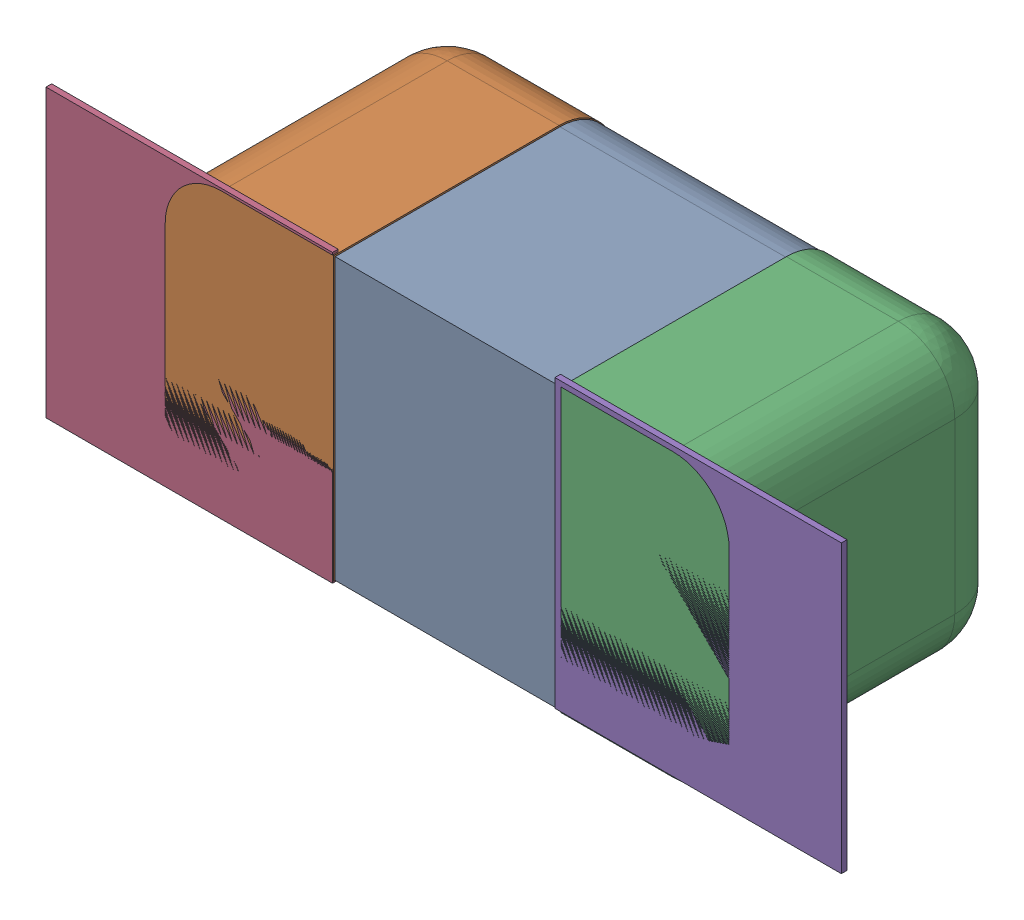
SolidWorks assembly C114, configuration Défaut. Lengths in mm.
Overall size (1.41 0.51 0.5).
8 component instances, 4 part files, 0 mates.
Components (placement in the parent):
- 5458962032-1: 5458962032 [Défaut] at (23.3934 -35.052 -2.0818) x (1 0 0) z (0 1 0) size (1 0.5 0.5)
  - Open CASCADE STEP translator 7.5 2.80.1.1-1: Open CASCADE STEP translator 7.5 2.80.1.1 [Défaut] at origin size (0.4 0.5 0.5)
  - Open CASCADE STEP translator 7.5 2.80.1.2-1: Open CASCADE STEP translator 7.5 2.80.1.2 [Défaut] at origin size (0.3 0.5 0.5)
  - Open CASCADE STEP translator 7.5 2.80.1.3-1: Open CASCADE STEP translator 7.5 2.80.1.3 [Défaut] at origin size (0.3 0.5 0.5)
- 6504207776-1: 6504207776 [Défaut] at (22.9361 -35.052 -2.0918) size (0.51 0.51 0.01)
  - Extruded-1: Extruded [Défaut] at origin size (0.51 0.51 0.01)
- 6504207776-2: 6504207776 [Défaut] at (23.8384 -35.0468 -2.0918) size (0.51 0.51 0.01)
  - Extruded-1: Extruded [Défaut] at origin size (0.51 0.51 0.01)
